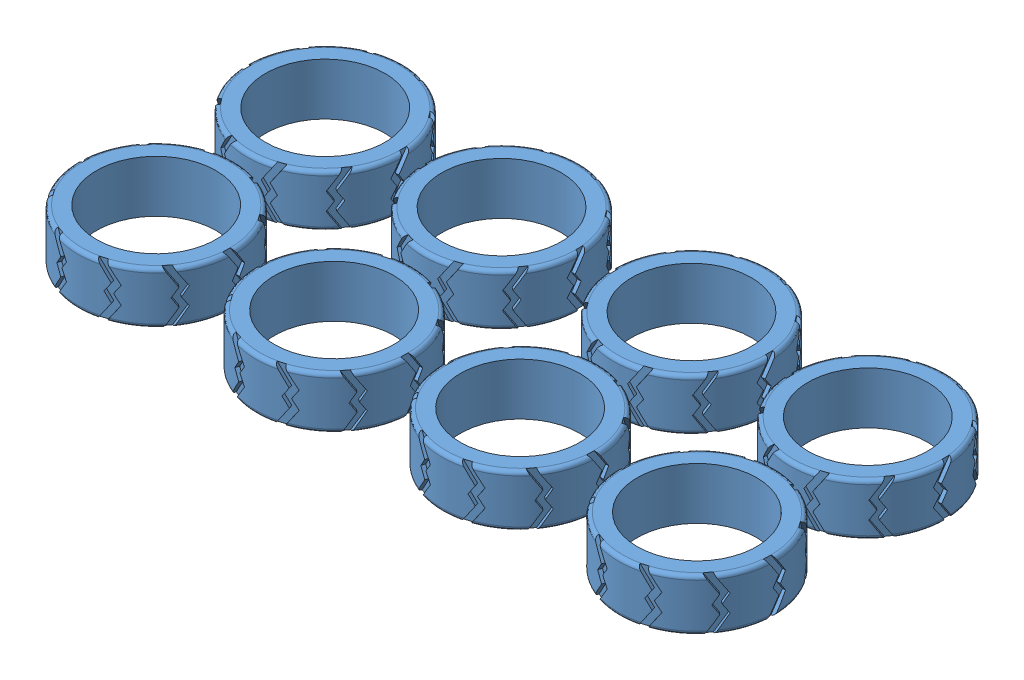
SolidWorks assembly All Tires, configuration Default. Lengths in mm.
Overall size (133.92 10.14 64.07).
8 component instances, 1 part files, 8 mates.
Components (placement in the parent):
- Tire-6: Tire [Default] at (-19.9349 0 34.888) x (0 -1 0) z (0 0 1) size (10.14 30.13 30)
- Tire-7: Tire [Default] at (-54.3464 0 34.515) x (0 -1 0) z (0 0 1) size (10.14 30.13 30)
- Tire-8: Tire [Default] at (-53.8315 10 2.0416) x (0 1 0) z (0 0 1) size (10.14 30.13 30)
- Tire-9: Tire [Default] at (-19.406 10 2.5184) x (0 1 0) z (0 0 1) size (10.14 30.13 30)
- Tire-14: Tire [Default] at (-89.5997 10 2.8411) x (0 1 0) z (0 0 1) size (10.14 30.13 30)
- Tire-15: Tire [Default] at (-88.5606 0 36.1067) x (0 -1 0) z (0 0 1) size (10.14 30.13 30)
- Tire-16: Tire [Default] at (-123.1961 0 35.7337) x (0 -1 0) z (0 0 1) size (10.14 30.13 30)
- Tire-17: Tire [Default] at (-123.1291 10 3.2603) x (0 1 0) z (0 0 1) size (10.14 30.13 30)
Mates (geometry in assembly coordinates):
- Coincident5: coincident: plane of Tire-6 through (-19.9349 0 19.888) normal (0 -1 0); plane of assembly through (0 0 0) normal (0 1 0)
- Coincident6: coincident: plane of Tire-7 through (-54.3464 0 19.515) normal (0 -1 0); plane of assembly through (0 0 0) normal (0 1 0)
- Coincident7: coincident: plane of Tire-8 through (-53.8315 0 -12.9584) normal (0 -1 0); plane of assembly through (0 0 0) normal (0 1 0)
- Coincident8: coincident: plane of Tire-9 through (-19.406 0 -12.4816) normal (0 -1 0); plane of assembly through (0 0 0) normal (0 1 0)
- Coincident11: coincident: plane of Tire-15 through (-88.5606 0 21.1067) normal (0 -1 0); plane of assembly
- Coincident13: coincident: plane of Tire-14 through (-89.5997 0 -12.1589) normal (0 -1 0); plane of assembly
- Coincident15: coincident: plane of Tire-16 through (-123.1961 0 20.7337) normal (0 -1 0); plane of assembly
- Coincident17: coincident: plane of Tire-17 through (-123.1291 0 -11.7397) normal (0 -1 0); plane of assembly
